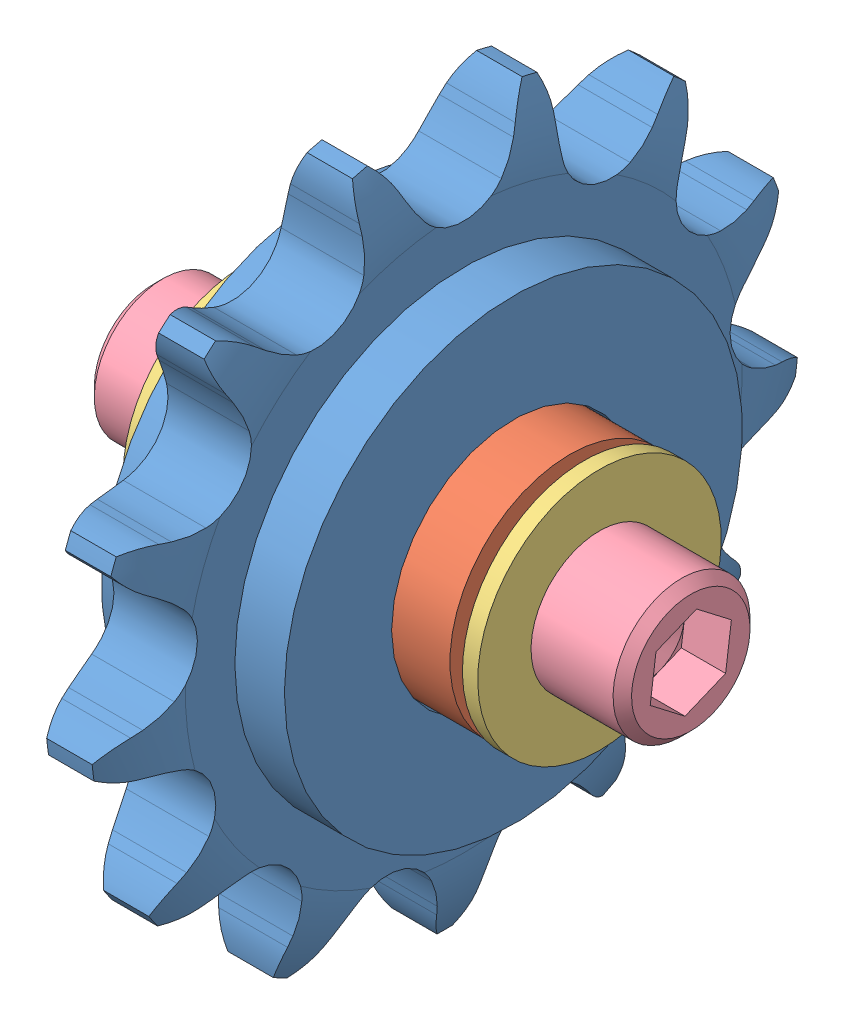
SolidWorks assembly IdlerSprocket, configuration Default. Lengths in mm.
Overall size (56.05 73.04 73.57).
8 component instances, 6 part files, 14 mates.
Components (placement in the parent):
- Precision Roller Chain Sprocket_AI-1: Precision Roller Chain Sprocket_AI [50-0.625P1ST13T13SB3.0H.75L1.0000N] at (-4.3695 0.0592 -0.0314) size (19.05 73.04 73.57)
- ChainTensionerShaft-1: ChainTensionerShaft [Default] at (0 0.0592 -0.0314) x (-1 0 0) z (0 -0.999999 -0.001383) size (30.8 25 25)
- Flat Washer Type B Regular_AI-1: Flat Washer Type B Regular_AI [Regular FW 0.375] at (-16.9 0.0592 -0.0314) size (1.6 25.4 25.4)
- Flat Washer Type B Regular_AI-2: Flat Washer Type B Regular_AI [Regular FW 0.375] at (16.9 0.0592 -0.0314) x (-1 0 0) z (0 0.201636 -0.979461) size (1.6 25.4 25.4)
- Socket Head Cap Screw_AI-1: Socket Head Cap Screw_AI [HX-SHCS 0.375-24x0.5x0.5-N] at (-28.0252 0.0592 -0.0314) x (1 0 0) z (0 -0.3979 0.917429) size (22.23 14.29 14.29)
- Socket Head Cap Screw_AI-2: Socket Head Cap Screw_AI [HX-SHCS 0.375-24x0.5x0.5-N] at (28.0252 0.0592 -0.0314) x (-1 0 0) z (0 0.924225 0.381849) size (22.23 14.29 14.29)
- Radial Ball Bearing_68_SKF-2: Radial Ball Bearing_68_SKF [SKF - 61805 - 22,SI,NC,22_68] at (0.6305 0.0592 -0.0314) x (-1 0 0) z (0 -0.513655 -0.857997) size (7 37 37)
- Basic Internal Retaining Ring_wti-2: Basic Internal Retaining Ring_wti [Truarc N5000-145 - S1.456] at (-2.8695 0.0592 -0.0314) x (0 0.556223 0.831033) z (-1 0 0) size (39.32 38.58 1.27)
Mates (geometry in assembly coordinates):
- Coincident1: coincident: plane of assembly through (0 0 0) normal (1 0 0); plane of ChainTensionerShaft-1 through (0 0.0592 -0.0314) normal (-1 0 0); plane of assembly
- Concentric1: concentric: cylinder of assembly; cylinder of assembly; cylinder of ChainTensionerShaft-1 through (15.4 0.0592 -0.0314) axis (-1 0 0) radius 12.5; cylinder of Precision Roller Chain Sprocket_AI-1 through (14.6805 0.0592 -0.0314) axis (-1 0 0) radius 12.7
- Concentric2: concentric: cylinder of assembly; cylinder of assembly; cylinder of ChainTensionerShaft-1 through (15.4 0.0592 -0.0314) axis (1 0 0) radius 4.2164; cylinder of Flat Washer Type B Regular_AI-1 through (-51.825 0.0592 -0.0314) axis (-1 0 0) radius 5.1562
- Distance1: distance = 1.5 mm: plane of assembly; plane of assembly; plane of ChainTensionerShaft-1 through (-15.4 0.0592 -0.0314) normal (-1 0 0); plane of Flat Washer Type B Regular_AI-1 through (-16.9 5.2154 -0.0314) normal (1 0 0)
- Concentric3: concentric: cylinder of assembly; cylinder of assembly; cylinder of ChainTensionerShaft-1 through (15.4 0.0592 -0.0314) axis (1 0 0) radius 4.2164; cylinder of Flat Washer Type B Regular_AI-2 through (51.825 0.0592 -0.0314) axis (1 0 0) radius 5.1562
- Distance2: distance = 1.5 mm: plane of assembly; plane of assembly; plane of ChainTensionerShaft-1 through (15.4 0.0592 -0.0314) normal (1 0 0); plane of Flat Washer Type B Regular_AI-2 through (16.9 5.1095 1.0082) normal (-1 0 0)
- Concentric4: concentric: cylinder of assembly; cylinder of assembly; cylinder of ChainTensionerShaft-1 through (15.4 0.0592 -0.0314) axis (1 0 0) radius 4.2164; cylinder of Socket Head Cap Screw_AI-1 through (-59.7752 0.0592 -0.0314) axis (-1 0 0) radius 7.1437
- Coincident4: coincident: plane of assembly; plane of assembly; plane of Flat Washer Type B Regular_AI-1 through (-18.5002 12.7592 -0.0314) normal (-1 0 0); plane of Socket Head Cap Screw_AI-1 through (-18.5002 6.613 2.8111) normal (1 0 0)
- Concentric5: concentric: cylinder of assembly; cylinder of assembly; cylinder of ChainTensionerShaft-1 through (15.4 0.0592 -0.0314) axis (1 0 0) radius 4.2164; cylinder of Socket Head Cap Screw_AI-2 through (59.7752 0.0592 -0.0314) axis (1 0 0) radius 7.1437
- Coincident5: coincident: plane of assembly; plane of assembly; plane of Flat Washer Type B Regular_AI-2 through (18.5002 12.4983 2.5293) normal (1 0 0); plane of Socket Head Cap Screw_AI-2 through (18.5002 -2.6687 6.571) normal (-1 0 0)
- Concentric7: concentric: cylinder of assembly; cylinder of assembly; cylinder of ChainTensionerShaft-1 through (15.4 0.0592 -0.0314) axis (-1 0 0) radius 12.5; cylinder of Radial Ball Bearing_68_SKF-2 through (21.268 0.0592 -0.0314) axis (-1 0 0) radius 12.5
- Distance3: distance = 6.6721 mm: plane of assembly; plane of assembly; plane of Radial Ball Bearing_68_SKF-2 through (-2.8695 15.6747 -9.38) normal (-1 0 0); plane of Precision Roller Chain Sprocket_AI-1 through (-9.5416 0.0592 -0.0314) normal (-1 0 0)
- Concentric8: concentric: circle of assembly; cylinder of assembly; circle of Precision Roller Chain Sprocket_AI-1; cylinder of Basic Internal Retaining Ring_wti-2 through (-1.5995 0.0592 -0.0314) axis (-1 0 0) radius 19.6596
- Coincident6: coincident: plane of assembly; plane of assembly; plane of Radial Ball Bearing_68_SKF-2 through (-2.8695 11.0415 -6.6062) normal (-1 0 0); plane of Basic Internal Retaining Ring_wti-2 through (-2.8695 0.0592 -0.0314) normal (-1 0 0)
